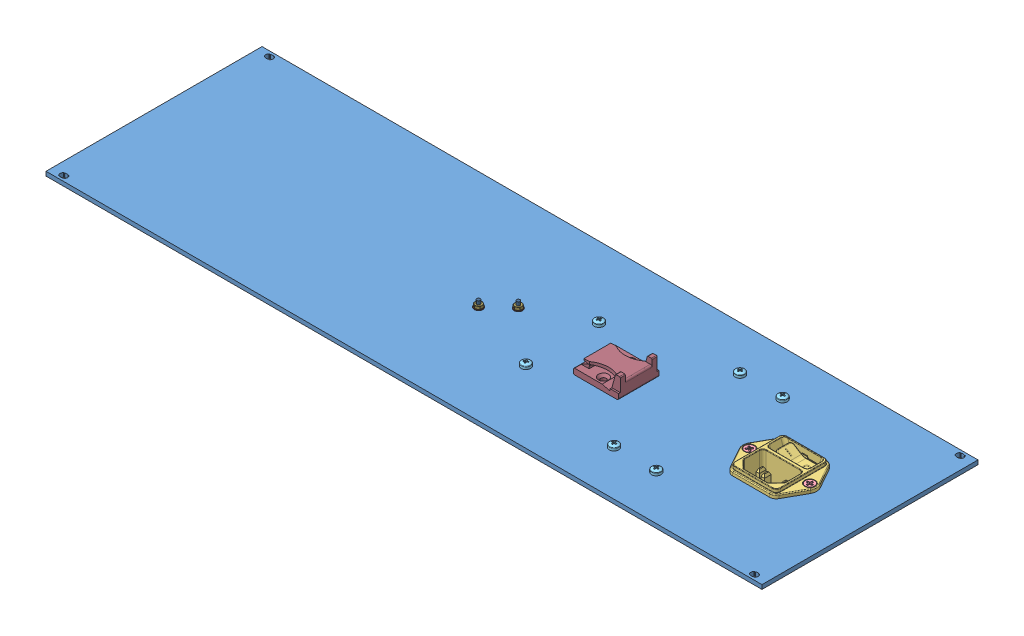
SolidWorks assembly MLA-0387-M2, configuration Default. Lengths in mm.
Overall size (426.52 43.75 128.7).
38 component instances, 15 part files, 74 mates.
Components (placement in the parent):
- MLA-0387-M3-1: MLA-0387-M3 [Default] at (14.077 -174.6299 585.4715) size (426.52 2.5 128.7)
- ECL15US12-S-1: ECL15US12-S [Default] at (340.987 202.9701 302.5215) x (0 0 -1) z (1 0 0) size (84 26.49 34.5)
- DC11_0001_001-1: DC11_0001_001 [Default] at (389.437 205.4701 308.5715) x (1 0 0) z (0 1 0) size (44 34 36.95)
- SCREW_ISO 7046-1: SCREW_ISO 7046 [VIJAK M 3x 10] at (371.437 207.6701 302.5215) x (0 -1 0) z (-0.609119 0 0.793079) size (10 5.6 5.6)
- SCREW_ISO 7046-2: SCREW_ISO 7046 [VIJAK M 3x 10] at (407.437 207.6701 302.5215) x (0 -1 0) z (0 0 1) size (10 5.6 5.6)
- M3 X 10mm Screw-1: M3 X 10mm Screw [Default] at (328.287 207.8701 340.0215) x (0 -1 0) z (0 0 1) size (12.61 5.6 5.6)
- M3 X 10mm Screw-2: M3 X 10mm Screw [Default] at (353.687 207.8701 340.2611) x (0 -1 0) z (0 0 1) size (12.61 5.6 5.6)
- M3 X 10mm Screw-3: M3 X 10mm Screw [Default] at (353.687 207.8701 265.0215) x (0 -1 0) z (0 0 1) size (12.61 5.6 5.6)
- M3 X 10mm Screw-4: M3 X 10mm Screw [Default] at (328.287 207.8701 265.0215) x (0 -1 0) z (0 0 1) size (12.61 5.6 5.6)
- M3 screw size FLAT WASHER-1: M3 screw size FLAT WASHER [Default] at (407.437 202.9701 302.5215) x (0.944963 0 -0.327176) z (0 -1 0) size (7 7 0.6)
- M3 screw size FLAT WASHER-2: M3 screw size FLAT WASHER [Default] at (371.437 202.3701 302.5215) x (1 0 0) z (0 1 0) size (7 7 0.6)
- M3 x 0.5mm Thread HEX NUT-1: M3 x 0.5mm Thread HEX NUT [Default] at (407.4348 201.1701 302.5562) x (1 0 0) z (0 1 0) size (5.5 6.35 2.6)
- M3 x 0.5mm Thread HEX NUT-2: M3 x 0.5mm Thread HEX NUT [Default] at (371.4463 201.1701 302.55) x (1 0 0) z (0 1 0) size (5.5 6.35 2.6)
- M3 screw size FLAT WASHER-3: M3 screw size FLAT WASHER [Default] at (353.687 199.8701 340.2611) x (1 0 0) z (0 1 0) size (7 7 0.6)
- M3 screw size FLAT WASHER-4: M3 screw size FLAT WASHER [Default] at (328.287 199.8701 340.0215) x (1 0 0) z (0 1 0) size (7 7 0.6)
- M3 screw size FLAT WASHER-5: M3 screw size FLAT WASHER [Default] at (328.287 200.4701 265.0215) x (1 0 0) z (0 -1 0) size (7 7 0.6)
- M3 screw size FLAT WASHER-6: M3 screw size FLAT WASHER [Default] at (353.687 200.4701 265.0215) x (1 0 0) z (0 -1 0) size (7 7 0.6)
- M3 x 0.5mm Thread HEX NUT-3: M3 x 0.5mm Thread HEX NUT [Default] at (328.3059 198.6701 265.0157) x (1 0 0) z (0 -1 0) size (5.5 6.35 2.6)
- M3 x 0.5mm Thread HEX NUT-4: M3 x 0.5mm Thread HEX NUT [Default] at (353.679 198.6701 264.9262) x (1 0 0) z (0 -1 0) size (5.5 6.35 2.6)
- M3 x 0.5mm Thread HEX NUT-5: M3 x 0.5mm Thread HEX NUT [Default] at (353.654 198.6701 340.285) x (1 0 0) z (0 1 0) size (5.5 6.35 2.6)
- M3 x 0.5mm Thread HEX NUT-6: M3 x 0.5mm Thread HEX NUT [Default] at (328.2745 198.6701 340.0301) x (1 0 0) z (0 1 0) size (5.5 6.35 2.6)
- MLA-0387-C1-1: MLA-0387-C1 [Default] at (14.9012 211.109 380.7327)
- MLA-0387-C2-1: MLA-0387-C2 [Default] at (65.7499 212.3525 388.3966)
- T9CP5A54-240-1: T9CP5A54-240 [Default] at (273.737 202.9701 327.6615) x (-1 0 0) z (0 0 1) size (27.43 27.94 50.29)
- WH5-10RJI-1: WH5-10RJI [Default] at (221.907 202.9701 302.5215) x (0 0 -1) z (-1 0 0) size (30 8.5 17)
- M3 X 10mm Screw-5: M3 X 10mm Screw [Default] at (260.022 207.8701 324.2715) x (0 -1 0) z (-0.906847 0 0.42146) size (12.61 5.6 5.6)
- M3 X 10mm Screw-6: M3 X 10mm Screw [Default] at (260.022 207.8701 280.7615) x (0 -1 0) z (-0.321237 0 0.946999) size (12.61 5.6 5.6)
- M3 screw size FLAT WASHER-7: M3 screw size FLAT WASHER [Default] at (260.022 200.9701 324.2715) x (0.984229 0 0.176899) z (0 -1 0) size (7 7 0.6)
- M3 x 0.5mm Thread HEX NUT-7: M3 x 0.5mm Thread HEX NUT [Default] at (260.022 199.1701 324.2715) x (0.946991 0 0.321261) z (0 1 0) size (5.5 6.35 2.6)
- M3 screw size FLAT WASHER-8: M3 screw size FLAT WASHER [Default] at (260.022 200.3701 280.7615) x (0.997885 0 0.065007) z (0 1 0) size (7 7 0.6)
- M3 x 0.5mm Thread HEX NUT-8: M3 x 0.5mm Thread HEX NUT [Default] at (260.022 199.1701 280.7615) x (0.997632 0 0.068783) z (0 1 0) size (5.5 6.35 2.6)
- M2x8 zaaggleuf-1: M2x8 zaaggleuf [Default] at (215.707 200.1701 308.1715) x (-0.042422 0 -0.9991) z (0.9991 0 -0.042422) size (3.8 9.3 3.8)
- M2x8 zaaggleuf-2: M2x8 zaaggleuf [Default] at (228.107 200.1701 296.8715) x (-0.58667 0 -0.809826) z (0.809826 0 -0.58667) size (3.8 9.3 3.8)
- M2 washer-2: M2 washer [Default] at (228.107 205.4701 296.8715) x (0.757822 0 0.652461) z (-0.652461 0 0.757822) size (5 0.3 5)
- M2 washer-3: M2 washer [Default] at (215.707 205.4701 308.1715) size (5 0.3 5)
- M2 Nut-1: M2 Nut [Default] at (228.107 207.3701 296.8715) x (1 0 0) z (0 1 0) size (4 4.62 1.6)
- M2 Nut-2: M2 Nut [Default] at (215.707 207.3701 308.1715) x (1 0 0) z (0 1 0) size (4 4.62 1.6)
- 060_16_QS-1: 060_16_QS [Default] at (278.487 205.4701 302.5215) x (1 0 0) z (0 1 0) size (27 24 11.5)
Mates (geometry in assembly coordinates):
- Coincident1: coincident anti-aligned: plane of MLA-0387-M3-1 through (22.1573 202.9701 282.3956) normal (0 -1 0); plane of ECL15US12-S-1 through (358.237 202.9701 335.5215) normal (0 1 0)
- Distance1: distance = 22.35 mm aligned: line of ECL15US12-S-1 through (324.7368 202.9701 344.5215) axis (1 0 0); plane of MLA-0387-M3-1 through (443.237 202.9701 366.8715) normal (0 0 1)
- Coincident8: coincident anti-aligned: plane of MLA-0387-M3-1 through (22.1573 205.4701 282.3956) normal (0 1 0); plane of DC11_0001_001-1 through (378.437 205.4701 289.5215) normal (0 -1 0)
- Concentric2: concentric anti-aligned: cylinder of MLA-0387-M3-1 through (371.437 212.9701 302.5215) axis (0 -1 0) radius 1.8; cylinder of DC11_0001_001-1 through (371.437 207.6701 302.5215) axis (0 1 0) radius 1.6
- Concentric3: concentric anti-aligned: cylinder of MLA-0387-M3-1 through (407.437 212.9701 302.5215) axis (0 -1 0) radius 1.8; cylinder of DC11_0001_001-1 through (407.437 207.6701 302.5215) axis (0 1 0) radius 1.6
- Distance4: distance = 85 mm: line of MLA-0387-M3-1 through (443.237 202.9701 366.8715) axis (0 0 -1); line of ECL15US12-S-1 through (358.237 202.9701 343.5217) axis (0 0 -1)
- Concentric4: concentric aligned: cone of DC11_0001_001-1 through (371.437 207.4701 302.5215) axis (0 -1 0); cone of SCREW_ISO 7046-1 through (371.437 206.1701 302.5215) axis (0 -1 0)
- Coincident9: coincident aligned: plane of DC11_0001_001-1 through (378.437 207.6701 289.5215) normal (0 1 0); plane of SCREW_ISO 7046-1 through (371.437 207.6701 302.5215) normal (0 1 0)
- Concentric5: concentric aligned: cone of DC11_0001_001-1 through (407.437 207.4701 302.5215) axis (0 -1 0); cone of SCREW_ISO 7046-2 through (407.437 206.1701 302.5215) axis (0 -1 0)
- Coincident10: coincident aligned: plane of DC11_0001_001-1 through (378.437 207.6701 289.5215) normal (0 1 0); plane of SCREW_ISO 7046-2 through (407.437 207.6701 302.5215) normal (0 1 0)
- Coincident11: coincident anti-aligned: plane of MLA-0387-M3-1 through (22.1573 205.4701 282.3956) normal (0 1 0); plane of M3 X 10mm Screw-1 through (328.287 205.4701 338.5215) normal (0 -1 0)
- Concentric6: concentric aligned: cylinder of MLA-0387-M3-1 through (328.287 212.9701 340.0215) axis (0 -1 0) radius 1.8; cylinder of M3 X 10mm Screw-1 through (328.287 195.4701 340.0215) axis (0 -1 0) radius 2.8
- Coincident12: coincident anti-aligned: plane of MLA-0387-M3-1 through (22.1573 205.4701 282.3956) normal (0 1 0); plane of M3 X 10mm Screw-2 through (353.687 205.4701 338.7611) normal (0 -1 0)
- Concentric7: concentric aligned: cylinder of MLA-0387-M3-1 through (353.687 212.9701 340.2611) axis (0 -1 0) radius 1.8; cylinder of M3 X 10mm Screw-2 through (353.687 195.4701 340.2611) axis (0 -1 0) radius 2.8
- Coincident13: coincident anti-aligned: plane of MLA-0387-M3-1 through (22.1573 205.4701 282.3956) normal (0 1 0); plane of M3 X 10mm Screw-3 through (353.687 205.4701 263.5215) normal (0 -1 0)
- Concentric8: concentric aligned: cylinder of MLA-0387-M3-1 through (353.687 212.9701 265.0215) axis (0 -1 0) radius 1.8; cylinder of M3 X 10mm Screw-3 through (353.687 195.4701 265.0215) axis (0 -1 0) radius 2.8
- Coincident14: coincident anti-aligned: plane of MLA-0387-M3-1 through (22.1573 205.4701 282.3956) normal (0 1 0); plane of M3 X 10mm Screw-4 through (328.287 205.4701 263.5215) normal (0 -1 0)
- Concentric9: concentric aligned: cylinder of MLA-0387-M3-1 through (328.287 212.9701 265.0215) axis (0 -1 0) radius 1.8; cylinder of M3 X 10mm Screw-4 through (328.287 195.4701 265.0215) axis (0 -1 0) radius 2.8
- Coincident15: coincident anti-aligned: plane of MLA-0387-M3-1 through (22.1573 202.9701 282.3956) normal (0 -1 0); plane of M3 screw size FLAT WASHER-1 through (407.437 202.9701 302.5215) normal (0 1 0)
- Concentric10: concentric anti-aligned: cylinder of M3 screw size FLAT WASHER-1 through (407.437 202.3701 302.5215) axis (0 1 0) radius 1.6; cylinder of SCREW_ISO 7046-2 through (407.437 197.6701 302.5215) axis (0 -1 0) radius 2.8
- Coincident16: coincident anti-aligned: plane of MLA-0387-M3-1 through (22.1573 202.9701 282.3956) normal (0 -1 0); plane of M3 screw size FLAT WASHER-2 through (371.437 202.9701 302.5215) normal (0 1 0)
- Concentric11: concentric aligned: cylinder of MLA-0387-M3-1 through (371.437 212.9701 302.5215) axis (0 -1 0) radius 1.8; cylinder of M3 screw size FLAT WASHER-2 through (371.437 202.9701 302.5215) axis (0 -1 0) radius 1.6
- Coincident17: coincident anti-aligned: plane of M3 screw size FLAT WASHER-1 through (407.437 202.3701 302.5215) normal (0 -1 0); plane of M3 x 0.5mm Thread HEX NUT-1 through (404.6848 202.3701 300.9685) normal (0 1 0)
- Coincident18: coincident anti-aligned: plane of M3 screw size FLAT WASHER-2 through (371.437 202.3701 302.5215) normal (0 -1 0); plane of M3 x 0.5mm Thread HEX NUT-2 through (368.6963 202.3701 300.9623) normal (0 1 0)
- Coincident19: coincident anti-aligned: plane of ECL15US12-S-1 through (358.237 200.4701 335.0215) normal (0 -1 0); plane of M3 screw size FLAT WASHER-3 through (353.687 200.4701 340.2611) normal (0 1 0)
- Concentric13: concentric aligned: cylinder of M3 X 10mm Screw-2 through (353.687 195.4701 340.2611) axis (0 -1 0) radius 2.8; cylinder of M3 screw size FLAT WASHER-3 through (353.687 200.4701 340.2611) axis (0 -1 0) radius 3.5
- Coincident20: coincident anti-aligned: plane of ECL15US12-S-1 through (358.237 200.4701 335.0215) normal (0 -1 0); plane of M3 screw size FLAT WASHER-4 through (328.287 200.4701 340.0215) normal (0 1 0)
- Concentric14: concentric aligned: cylinder of M3 X 10mm Screw-1 through (328.287 195.4701 340.0215) axis (0 -1 0) radius 2.8; cylinder of M3 screw size FLAT WASHER-4 through (328.287 200.4701 340.0215) axis (0 -1 0) radius 3.5
- Coincident21: coincident anti-aligned: plane of ECL15US12-S-1 through (358.237 200.4701 270.0215) normal (0 -1 0); plane of M3 screw size FLAT WASHER-5 through (328.287 200.4701 265.0215) normal (0 1 0)
- Concentric15: concentric aligned: cylinder of M3 X 10mm Screw-4 through (328.287 195.4701 265.0215) axis (0 -1 0) radius 2.8; circle of M3 screw size FLAT WASHER-5
- Coincident22: coincident anti-aligned: plane of ECL15US12-S-1 through (358.237 200.4701 270.0215) normal (0 -1 0); plane of M3 screw size FLAT WASHER-6 through (353.687 200.4701 265.0215) normal (0 1 0)
- Concentric16: concentric anti-aligned: circle of M3 X 10mm Screw-3; cylinder of M3 screw size FLAT WASHER-6 through (353.687 199.8701 265.0215) axis (0 1 0) radius 3.5
- Coincident24: coincident anti-aligned: plane of M3 screw size FLAT WASHER-5 through (328.287 199.8701 265.0215) normal (0 -1 0); plane of M3 x 0.5mm Thread HEX NUT-3 through (325.5559 199.8701 266.6034) normal (0 1 0)
- Coincident25: coincident anti-aligned: plane of M3 screw size FLAT WASHER-6 through (353.687 199.8701 265.0215) normal (0 -1 0); plane of M3 x 0.5mm Thread HEX NUT-4 through (350.929 199.8701 266.5139) normal (0 1 0)
- Coincident26: coincident anti-aligned: plane of M3 screw size FLAT WASHER-3 through (353.687 199.8701 340.2611) normal (0 -1 0); plane of M3 x 0.5mm Thread HEX NUT-5 through (350.904 199.8701 338.6973) normal (0 1 0)
- Coincident27: coincident anti-aligned: plane of M3 screw size FLAT WASHER-4 through (328.287 199.8701 340.0215) normal (0 -1 0); plane of M3 x 0.5mm Thread HEX NUT-6 through (325.5245 199.8701 338.4424) normal (0 1 0)
- Coincident28: coincident anti-aligned: plane of MLA-0387-M3-1 through (22.1573 202.9701 282.3956) normal (0 -1 0); plane of T9CP5A54-240-1 through (273.737 202.9701 327.6615) normal (0 1 0)
- Distance6: distance = 39.2 mm aligned: plane of MLA-0387-M3-1 through (16.717 202.9701 238.1715) normal (0 0 -1); plane of T9CP5A54-240-1 through (273.737 200.9701 277.3715) normal (0 0 -1)
- Distance7: distance = 50 mm: line of ECL15US12-S-1 through (323.737 202.9701 261.5213) axis (0 0 1); plane of T9CP5A54-240-1 through (273.737 200.9701 327.6615) normal (1 0 0)
- Coincident34: coincident anti-aligned: plane of MLA-0387-M3-1 through (22.1573 202.9701 282.3956) normal (0 -1 0); plane of WH5-10RJI-1 through (221.907 202.9701 302.5215) normal (0 1 0)
- Distance8: distance = 20 mm anti-aligned: plane of WH5-10RJI-1 through (226.307 194.4701 294.0215) normal (1 0 0); plane of T9CP5A54-240-1 through (246.307 200.9701 327.6615) normal (-1 0 0)
- Distance9: distance = 55.85 mm: plane of MLA-0387-M3-1 through (16.717 202.9701 238.1715) normal (0 0 -1); moEndPointRef_w of WH5-10RJI-1
- Concentric18: concentric aligned: circle of MLA-0387-M3-1; circle of M3 X 10mm Screw-5
- Coincident35: coincident anti-aligned: plane of MLA-0387-M3-1 through (22.1573 205.4701 282.3956) normal (0 1 0); circle of M3 X 10mm Screw-5
- Concentric19: concentric aligned: circle of MLA-0387-M3-1; circle of M3 X 10mm Screw-6
- Coincident37: coincident anti-aligned: plane of MLA-0387-M3-1 through (22.1573 205.4701 282.3956) normal (0 1 0); plane of M3 X 10mm Screw-6 through (260.5038 205.4701 279.341) normal (0 -1 0)
- Concentric20: concentric anti-aligned: circle of MLA-0387-M3-1; circle of M3 screw size FLAT WASHER-7
- Coincident38: coincident aligned: plane of T9CP5A54-240-1 through (273.737 200.9701 327.6615) normal (0 -1 0); circle of M3 screw size FLAT WASHER-7
- Concentric21: concentric anti-aligned: circle of M3 screw size FLAT WASHER-7; circle of M3 x 0.5mm Thread HEX NUT-7
- Coincident39: coincident anti-aligned: plane of M3 screw size FLAT WASHER-7 through (260.022 200.3701 324.2715) normal (0 -1 0); plane of M3 x 0.5mm Thread HEX NUT-7 through (257.9278 200.3701 321.8845) normal (0 1 0)
- Concentric22: concentric anti-aligned: circle of MLA-0387-M3-1; circle of M3 screw size FLAT WASHER-8
- Coincident40: coincident anti-aligned: plane of T9CP5A54-240-1 through (273.737 200.9701 327.6615) normal (0 -1 0); plane of M3 screw size FLAT WASHER-8 through (260.022 200.9701 280.7615) normal (0 1 0)
- Concentric23: concentric anti-aligned: circle of M3 screw size FLAT WASHER-8; circle of M3 x 0.5mm Thread HEX NUT-8
- Coincident41: coincident anti-aligned: plane of M3 screw size FLAT WASHER-8 through (260.022 200.3701 280.7615) normal (0 -1 0); plane of M3 x 0.5mm Thread HEX NUT-8 through (257.3877 200.3701 278.9884) normal (0 1 0)
- Coincident42: coincident anti-aligned: plane of WH5-10RJI-1 through (221.707 201.4701 302.5215) normal (0 -1 0); plane of ? through (215.507 201.4701 308.1715) normal (0 1 0)
- Concentric25: concentric aligned: circle of MLA-0387-M3-1; circle of ?
- Coincident43: coincident anti-aligned: plane of MLA-0387-M3-1 through (22.1573 205.4701 282.3956) normal (0 1 0); plane of ? through (227.907 205.4701 296.8715) normal (0 -1 0)
- Concentric26: concentric aligned: cylinder of WH5-10RJI-1 through (215.507 201.4701 308.1715) axis (0 1 0) radius 1.2; cylinder of ? through (215.507 200.3815 308.1715) axis (0 1 0) radius 1.1
- Concentric27: concentric aligned: circle of WH5-10RJI-1; circle of ?
- Concentric28: concentric anti-aligned: circle of WH5-10RJI-1; cylinder of M2x8 zaaggleuf-1 through (215.707 209.4701 308.1715) axis (0 -1 0) radius 1
- Coincident44: coincident anti-aligned: plane of WH5-10RJI-1 through (221.907 201.4701 302.5215) normal (0 -1 0); plane of M2x8 zaaggleuf-1 through (215.707 201.4701 308.1715) normal (0 1 0)
- Concentric29: concentric aligned: circle of WH5-10RJI-1; circle of M2x8 zaaggleuf-2
- Coincident45: coincident anti-aligned: plane of WH5-10RJI-1 through (221.907 201.4701 302.5215) normal (0 -1 0); circle of M2x8 zaaggleuf-2
- Concentric30: concentric anti-aligned: cylinder of M2x8 zaaggleuf-2 through (228.107 209.4701 296.8715) axis (0 -1 0) radius 1; cylinder of M2 washer-2 through (228.107 205.4701 296.8715) axis (0 1 0) radius 1.1
- Coincident46: coincident: plane of MLA-0387-M3-1 through (22.1573 205.4701 282.3956) normal (0 1 0); moEndPointRef_w of M2 washer-2
- Coincident47: coincident anti-aligned: plane of MLA-0387-M3-1 through (22.1573 205.4701 282.3956) normal (0 1 0); plane of M2 washer-3 through (215.707 205.4701 308.1715) normal (0 -1 0)
- Concentric31: concentric anti-aligned: cylinder of M2x8 zaaggleuf-1 through (215.707 209.4701 308.1715) axis (0 -1 0) radius 1; circle of M2 washer-3
- Coincident49: coincident anti-aligned: cylinder of M2x8 zaaggleuf-2 through (228.107 209.4701 296.8715) axis (0 -1 0) radius 1; circle of M2 Nut-1
- Coincident50: coincident anti-aligned: plane of M2 washer-2 through (228.107 205.7701 296.8715) normal (0 1 0); plane of M2 Nut-1 through (228.107 205.7701 294.5621) normal (0 -1 0)
- Coincident51: coincident anti-aligned: plane of M2 washer-3 through (215.707 205.7701 308.1715) normal (0 1 0); plane of M2 Nut-2 through (215.707 205.7701 305.8621) normal (0 -1 0)
- Concentric32: concentric anti-aligned: cylinder of M2x8 zaaggleuf-1 through (215.707 209.4701 308.1715) axis (0 -1 0) radius 1; circle of M2 Nut-2
- Coincident52: coincident: plane of MLA-0387-M3-1 through (22.1573 205.4701 282.3956) normal (0 1 0); plane of 060_16_QS-1 through (295.5979 205.4701 291.9579) normal (0 -1 0)
- Coincident55: coincident: circle of MLA-0387-M3-1; cylinder of 060_16_QS-1 through (292.487 207.2201 294.5215) axis (0 -1 0) radius 1.6
- Concentric33: concentric anti-aligned: cylinder of MLA-0387-M3-1 through (292.487 195.4701 310.5215) axis (0 1 0) radius 1.6; cylinder of 060_16_QS-1 through (292.487 207.2201 310.5215) axis (0 -1 0) radius 1.6
